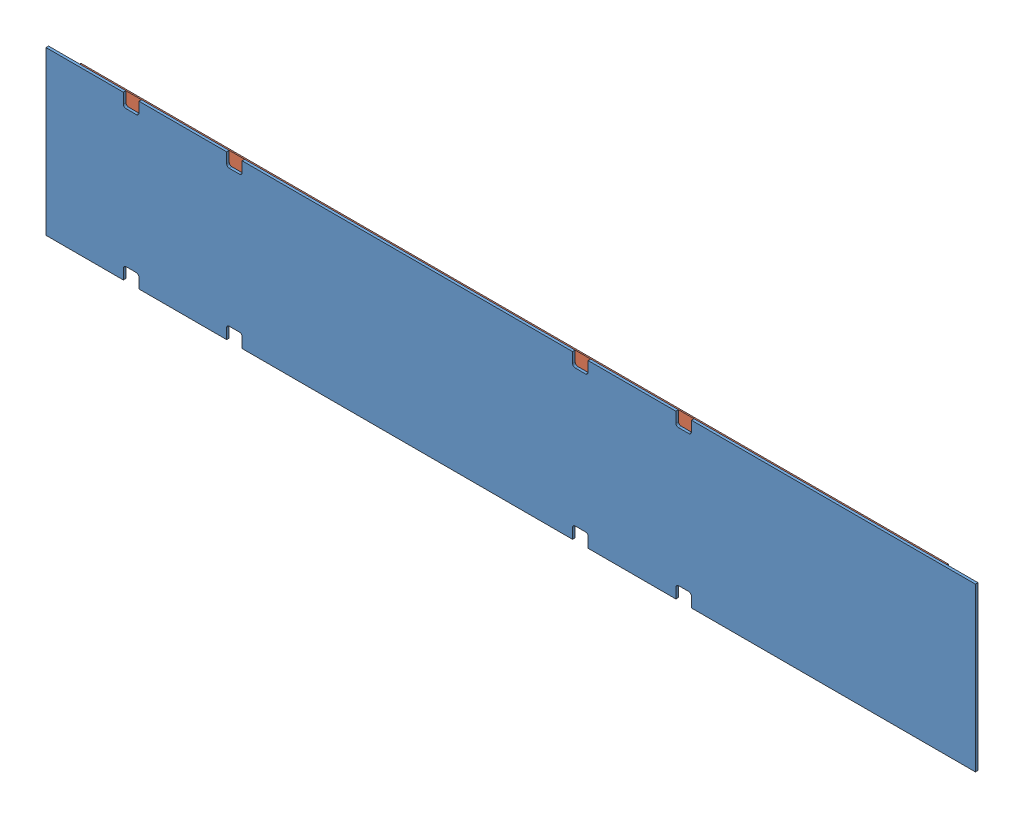
SolidWorks assembly GE-19229, configuration Default. Lengths in mm.
Overall size (1143 200.03 4.76).
4 component instances, 4 part files, 9 mates.
Components (placement in the parent):
- GE-19229-1: GE-19229 [Default] at origin size (1143 200.03 3.17)
- Loop_1_42-1: Loop_1_42 [Default] at (-533.4 100.0125 0) x (1 0 0) z (0 1 0) size (1066.8 1.59 25.4)
- Loop_1_9-1: Loop_1_9 [Default] at (241.3 -100.0125 -1.5875) x (1 0 0) z (0 -1 0) size (228.6 1.59 25.4)
- Loop_1_15-1: Loop_1_15 [Default] at (-317.5 -100.0125 -1.5875) x (1 0 0) z (0 -1 0) size (381 1.59 25.4)
Mates (geometry in assembly coordinates):
- Coincident2: coincident: plane of GE-19229-1 through (-571.5 100.0125 3.175) normal (0 1 0); plane of Loop_1_42-1 through (-533.4 100.0125 -1.5875) normal (0 1 0)
- Width1: width: plane of Loop_1_42-1 through (533.4 100.0125 -1.5875) normal (1 0 0); plane of Loop_1_42-1 through (-533.4 100.0125 -1.5875) normal (-1 0 0); plane of GE-19229-1 through (-571.5 -100.0125 3.175) normal (-1 0 0); plane of GE-19229-1 through (571.5 -100.0125 3.175) normal (1 0 0)
- Coincident3: coincident: plane of GE-19229-1 through (0 0 0) normal (0 0 -1); plane of Loop_1_42-1 through (-533.4 100.0125 0) normal (0 0 1)
- Coincident4: coincident: plane of GE-19229-1 through (0 0 0) normal (0 0 -1); plane of Loop_1_9-1 through (241.3 -100.0125 0) normal (0 0 1)
- Coincident5: coincident: plane of GE-19229-1 through (-571.5 -100.0125 3.175) normal (0 -1 0); plane of Loop_1_9-1 through (241.3 -100.0125 0) normal (0 -1 0)
- Coincident6: coincident: plane of GE-19229-1 through (0 0 0) normal (0 0 -1); plane of Loop_1_15-1 through (-317.5 -100.0125 0) normal (0 0 1)
- Coincident7: coincident: plane of GE-19229-1 through (-571.5 -100.0125 3.175) normal (0 -1 0); plane of Loop_1_15-1 through (-317.5 -100.0125 0) normal (0 -1 0)
- Distance1: distance = 254 mm: plane of Loop_1_15-1 through (-317.5 -100.0125 0) normal (-1 0 0); plane of GE-19229-1 through (-571.5 -100.0125 3.175) normal (-1 0 0)
- Distance2: distance = 177.8 mm: plane of assembly; plane of assembly; plane of Loop_1_9-1 through (241.3 -100.0125 0) normal (-1 0 0); plane of Loop_1_15-1 through (63.5 -100.0125 0) normal (1 0 0)
